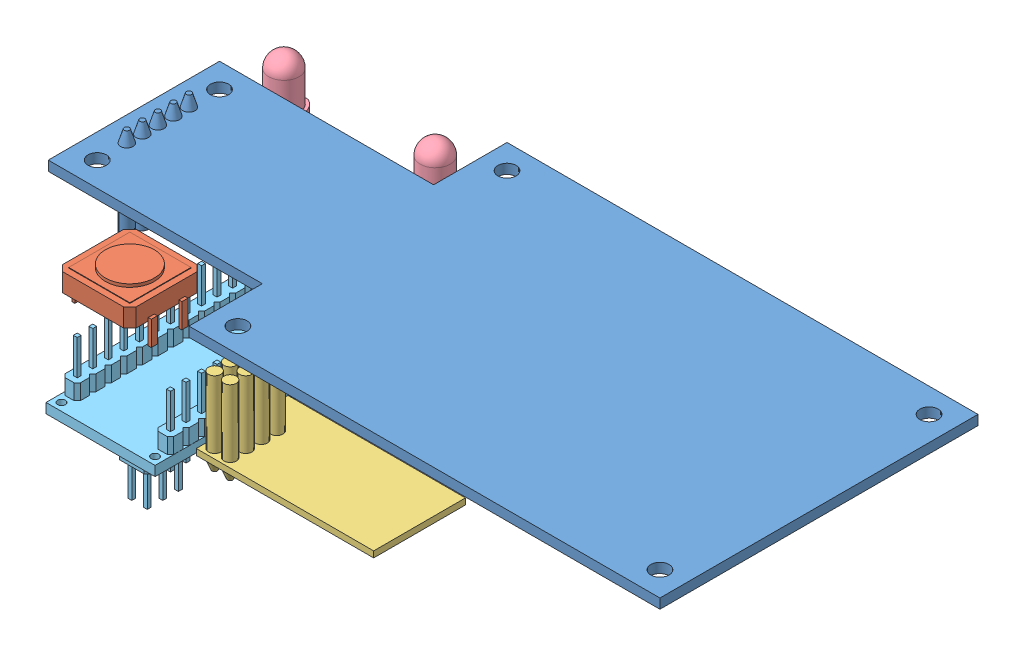
SolidWorks assembly Assemblage1, configuration Défaut. Lengths in mm.
Overall size (112 35.91 52).
7 component instances, 6 part files, 14 mates.
Components (placement in the parent):
- lecteur rfid-1: lecteur rfid [Défaut] at (-37.0495 15.1347 112) size (112 15 52)
- bouton-1: bouton [Défaut] at (-58.9958 10.8239 111.7134) size (13 7.1 12)
- module rf-1: module rf [Défaut] at (-43.1493 -7.2963 89.7011) x (1 0 0) z (0 0 -1) size (29 15 15)
- red-led-5mm-1: red-led-5mm [Default] at (-40.7506 11.3989 68.029) x (1 0 0) z (0 1 0) size (5.95 5.62 28.7)
- red-led-5mm-2: red-led-5mm [Default] at (-65.4936 11.3989 68.029) x (1 0 0) z (0 1 0) size (5.95 5.62 28.7)
- User Library-ArduinoMicro-1: User Library-ArduinoMicro [Default] at (-53.0361 -7.2963 86.3385) x (0 0 -1) z (-1 0 0) size (49.28 17.35 17.83)
- Pièce1^Assemblage1-1: Pièce1^Assemblage1 [Défaut] at (-55.0495 3.9183 86.3845) x (1 0 0) z (0 0 -1) (virtual)
Mates (geometry in assembly coordinates):
- Parallèle1: parallel: plane of lecteur rfid-1 through (-37.0495 15.1347 112) normal (0 -1 0); plane of module rf-1 through (-43.1493 -7.2963 89.7011) normal (0 1 0)
- Parallèle3: parallel: plane of lecteur rfid-1 through (-37.0495 16.7347 100) normal (0 0 1); plane of module rf-1 through (-43.1493 -8.2963 104.7011) normal (0 0 1)
- Parallèle4: parallel: plane of lecteur rfid-1 through (-37.0495 16.7347 112) normal (0 1 0); plane of red-led-5mm-1 through (-40.7506 10.8239 68.029) normal (0 -1 0)
- Parallèle5: parallel: plane of red-led-5mm-1 through (-40.7506 10.8239 68.029) normal (0 -1 0); plane of red-led-5mm-2 through (-65.4936 10.8239 68.029) normal (0 -1 0)
- Coïncidente8: coincident: plane of red-led-5mm-1 through (-45.3495 14.4769 65.389) normal (0 0 -1); plane of red-led-5mm-2 through (-70.0925 14.4769 65.389) normal (0 0 -1)
- Coïncidente10: coincident: line of red-led-5mm-1 through (-39.3791 11.9739 65.389) axis (-1 0 0); line of red-led-5mm-2 through (-64.1221 11.9739 65.389) axis (-1 0 0)
- Distance1: distance = 22 mm: line of red-led-5mm-1 through (-42.1221 10.8239 65.389) axis (0 1 0); line of red-led-5mm-2 through (-64.1221 11.9739 65.389) axis (0 -1 0)
- Coïncidente12: coincident: plane of bouton-1 through (-58.9958 10.8239 111.7134) normal (0 -1 0); plane of red-led-5mm-1 through (-40.7506 10.8239 68.029) normal (0 -1 0)
- Parallèle6: parallel: plane of lecteur rfid-1 through (-37.0495 15.1347 112) normal (0 -1 0); plane of User Library-ArduinoMicro-1 through (-53.0361 -7.2963 86.3385) normal (0 1 0)
- Coïncidente15: coincident: plane of module rf-1 through (-43.1493 -7.2963 89.7011) normal (0 1 0); plane of User Library-ArduinoMicro-1 through (-53.0361 -7.2963 86.3385) normal (0 1 0)
- Parallèle8: parallel: plane of lecteur rfid-1 through (-72.0495 16.7347 112) normal (-1 0 0); plane of User Library-ArduinoMicro-1 through (-61.9515 -8.8965 110.4685) normal (-1 0 0)
- Parallèle10: parallel: plane of lecteur rfid-1 through (-37.0495 15.1347 112) normal (0 -1 0); plane of Pièce1^Assemblage1-1 through (-55.0495 0 86.3845) normal (0 1 0)
- Parallèle11: parallel: plane of lecteur rfid-1 through (-37.0495 16.7347 60) normal (0 0 -1); plane of Pièce1^Assemblage1-1 through (-55.0495 -1.6 61) normal (0 0 -1)
- Coaxiale3: concentric: cylinder of lecteur rfid-1 through (-68.0495 15.1337 96) axis (0 1 0) radius 1.5; cylinder of Pièce1^Assemblage1-1 through (-68.0495 -1.6 96) axis (0 1 0) radius 1.5
